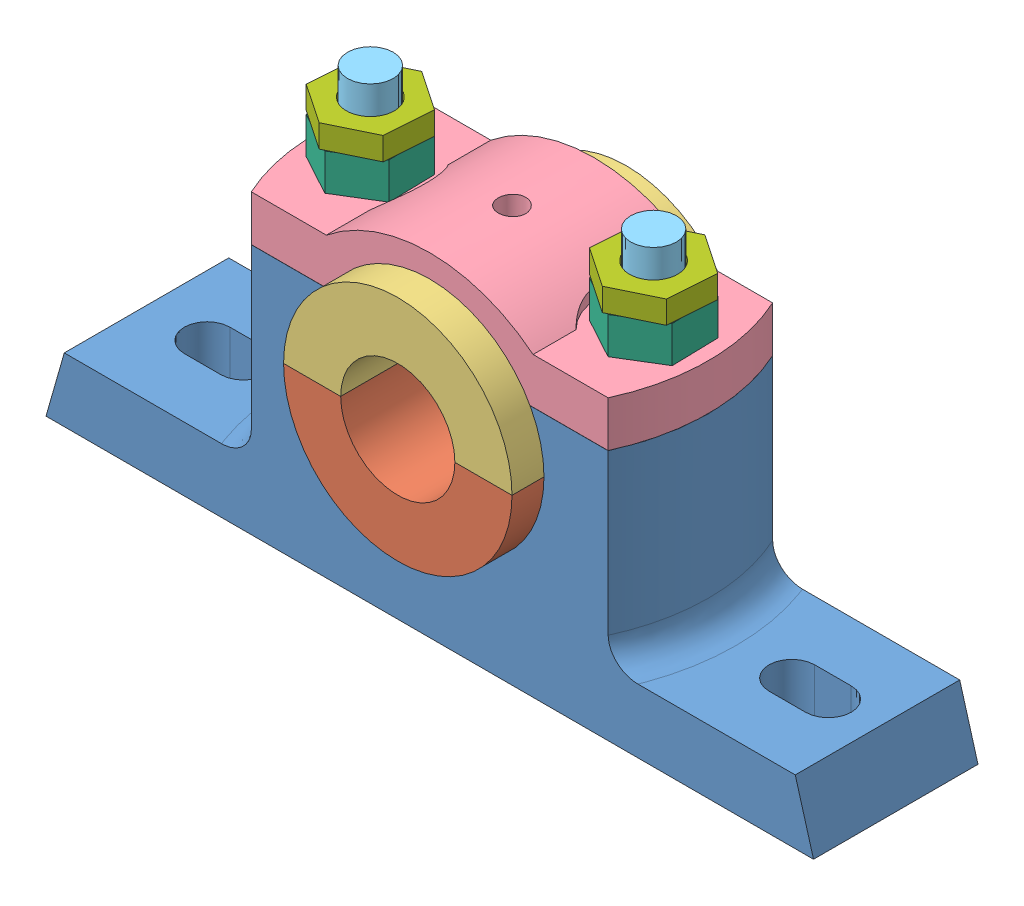
SolidWorks assembly Assem3, configuration Default. Lengths in mm.
Overall size (168 84 50).
10 component instances, 7 part files, 23 mates.
Components (placement in the parent):
- Part1-1: Part1 [Default] at (-9.8796 53.4112 109.5366) size (168 54.97 36)
- Part4-3: Part4 [Default] at (61.6204 96.4112 102.5366) x (0 0 1) z (0 -1 0) size (50 50 25)
- Part3-1: Part3 [Default] at (74.1204 96.4112 102.5366) x (0 0 1) z (0 1 0) size (50 50 25)
- Part6-1: Part6 [Default] at (74.1099 90.4112 109.5366) size (86 30 36)
- bolt-1: bolt [Default] at (43.1204 62.4112 127.5366) x (-1 0 0) z (0 0 1) size (18 81.5 17)
- bolt-2: bolt [Default] at (105.1099 62.4112 127.5366) x (0 0 -1) z (-1 0 0) size (18 81.5 17)
- Part7-1: Part7 [Default] at (105.1099 118.4112 127.5366) x (1 0 0) z (0 1 0) size (17.95 20.44 8)
- Part7-2: Part7 [Default] at (43.1204 118.4112 127.5366) x (1 0 0) z (0 1 0) size (17.95 20.44 8)
- Part8-1: Part8 [Default] at (105.1099 126.4112 127.5366) x (0.860231 0 -0.509905) z (0 1 0) size (20.94 19 5)
- Part8-2: Part8 [Default] at (43.1204 126.4112 127.5366) x (0.860231 0 -0.509905) z (0 1 0) size (20.94 19 5)
Mates (geometry in assembly coordinates):
- Coincident7: coincident anti-aligned: plane of Part1-1 through (74.1204 96.4112 145.5366) normal (0 0 1); plane of Part4-3 through (99.1204 96.4112 145.5366) normal (0 0 -1)
- Coincident8: coincident aligned: plane of Part1-1 through (93.1204 96.4112 145.5366) normal (0 1 0); plane of Part4-3 through (86.6204 96.4112 102.5366) normal (0 1 0)
- Concentric10: concentric aligned: cylinder of Part1-1 through (74.1204 96.4112 145.5366) axis (0 0 -1) radius 19; cylinder of Part4-3 through (74.1204 96.4112 129.2746) axis (0 0 -1) radius 19
- Coincident9: coincident anti-aligned: axis of Part1-1 through (74.1204 73.4112 127.5366) axis (0 1 0); axis of Part3-1 through (74.1204 113.9112 127.5366) axis (0 -1 0)
- Coincident10: coincident aligned: plane of Part4-3 through (86.6204 96.4112 152.5366) normal (0 0 1); plane of Part3-1 through (61.6204 96.4112 152.5366) normal (0 0 1)
- Coincident11: coincident anti-aligned: plane of Part4-3 through (86.6204 96.4112 102.5366) normal (0 1 0); plane of Part3-1 through (74.1204 96.4112 102.5366) normal (0 -1 0)
- Coincident12: coincident anti-aligned: plane of Part1-1 through (93.1204 96.4112 145.5366) normal (0 1 0); plane of Part6-1 through (74.1099 96.4112 145.5366) normal (0 -1 0)
- Coincident13: coincident anti-aligned: plane of Part1-1 through (96.1099 96.4112 145.5366) normal (-1 0 0); plane of Part6-1 through (96.1099 90.4112 145.5366) normal (1 0 0)
- Coincident14: coincident aligned: plane of Part1-1 through (74.1204 96.4112 145.5366) normal (0 0 1); plane of Part6-1 through (74.1099 90.4112 145.5366) normal (0 0 1)
- Coincident15: coincident aligned: axis of Part1-1 through (43.1204 108.3802 127.5366) axis (0 -1 0); axis of bolt-1 through (43.1204 137.4112 127.5366) axis (0 -1 0)
- Coincident16: coincident anti-aligned: plane of Part1-1 through (-9.8796 62.4112 109.5366) normal (0 -1 0); plane of bolt-1 through (43.1204 62.4112 136.0366) normal (0 1 0)
- Parallel3: parallel anti-aligned: plane of Part1-1 through (53.1204 62.4112 137.5366) normal (-1 0 0); plane of bolt-1 through (52.1204 62.4112 136.0366) normal (1 0 0)
- Coincident18: coincident anti-aligned: axis of Part6-1 through (105.1099 108.4112 127.5366) axis (0 1 0); axis of bolt-2 through (105.1099 137.4112 127.5366) axis (0 -1 0)
- Coincident19: coincident anti-aligned: plane of Part1-1 through (-9.8796 62.4112 109.5366) normal (0 -1 0); plane of bolt-2 through (96.6099 62.4112 127.5366) normal (0 1 0)
- Parallel4: parallel anti-aligned: plane of Part1-1 through (115.1204 62.4112 137.5366) normal (-1 0 0); plane of bolt-2 through (113.6099 62.4112 127.5366) normal (1 0 0)
- Coincident21: coincident anti-aligned: axis of bolt-2 through (105.1099 137.4112 127.5366) axis (0 -1 0); axis of Part7-1 through (105.1099 118.4112 127.5366) axis (0 1 0)
- Coincident22: coincident anti-aligned: plane of Part6-1 through (74.1099 118.4112 145.5366) normal (0 1 0); plane of Part7-1 through (105.1099 118.4112 127.5366) normal (0 -1 0)
- Coincident23: coincident anti-aligned: axis of bolt-1 through (43.1204 137.4112 127.5366) axis (0 -1 0); axis of Part7-2 through (43.1204 118.4112 127.5366) axis (0 1 0)
- Coincident24: coincident anti-aligned: plane of Part6-1 through (74.1099 118.4112 145.5366) normal (0 1 0); plane of Part7-2 through (43.1204 118.4112 127.5366) normal (0 -1 0)
- Coincident27: coincident anti-aligned: axis of bolt-2 through (105.1099 137.4112 127.5366) axis (0 -1 0); axis of Part8-1 through (105.1099 126.4112 127.5366) axis (0 1 0)
- Coincident29: coincident anti-aligned: plane of Part7-1 through (105.1099 126.4112 127.5366) normal (0 1 0); plane of Part8-1 through (105.1099 126.4112 127.5366) normal (0 -1 0)
- Coincident30: coincident anti-aligned: axis of bolt-1 through (43.1204 137.4112 127.5366) axis (0 -1 0); axis of Part8-2 through (43.1204 126.4112 127.5366) axis (0 1 0)
- Coincident31: coincident anti-aligned: plane of Part7-2 through (43.1204 126.4112 127.5366) normal (0 1 0); plane of Part8-2 through (43.1204 126.4112 127.5366) normal (0 -1 0)
